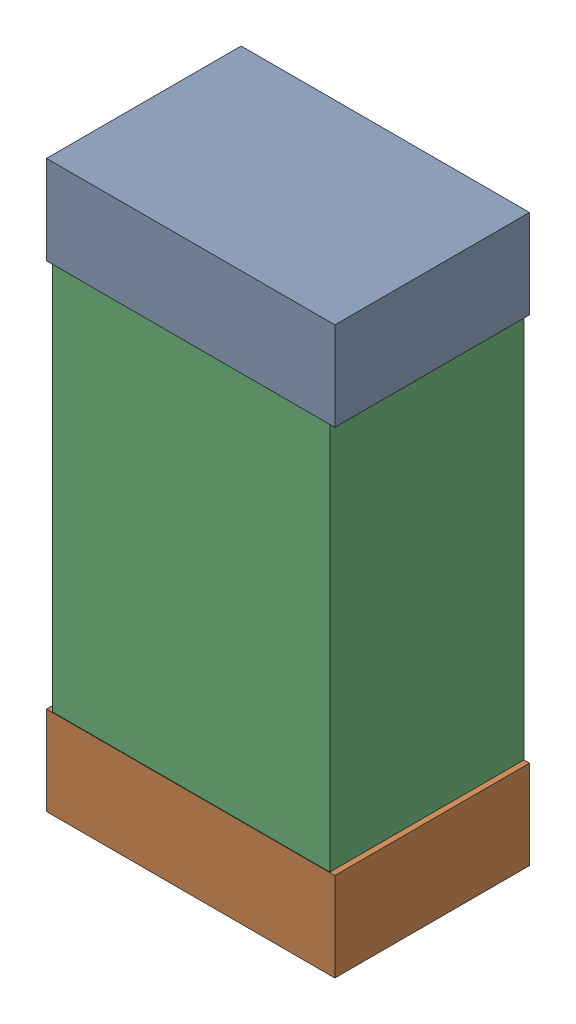
SolidWorks assembly C8, configuration Default. Lengths in mm.
Overall size (0.52 1.02 0.35).
6 component instances, 2 part files, 0 mates.
Components (placement in the parent):
- 870941120-1: 870941120 [Default] at (59.0288 26.4882 0) size (0.52 0.16 0.35)
  - Extruded_3-1: Extruded_3 [Default] at origin size (0.52 0.16 0.35)
- 870941120-2: 870941120 [Default] at (59.0288 25.6282 0) size (0.52 0.16 0.35)
  - Extruded_3-1: Extruded_3 [Default] at origin size (0.52 0.16 0.35)
- 870941280-1: 870941280 [Default] at (59.0288 26.0582 0) size (0.5 1 0.35)
  - Extruded_4-1: Extruded_4 [Default] at origin size (0.5 1 0.35)
